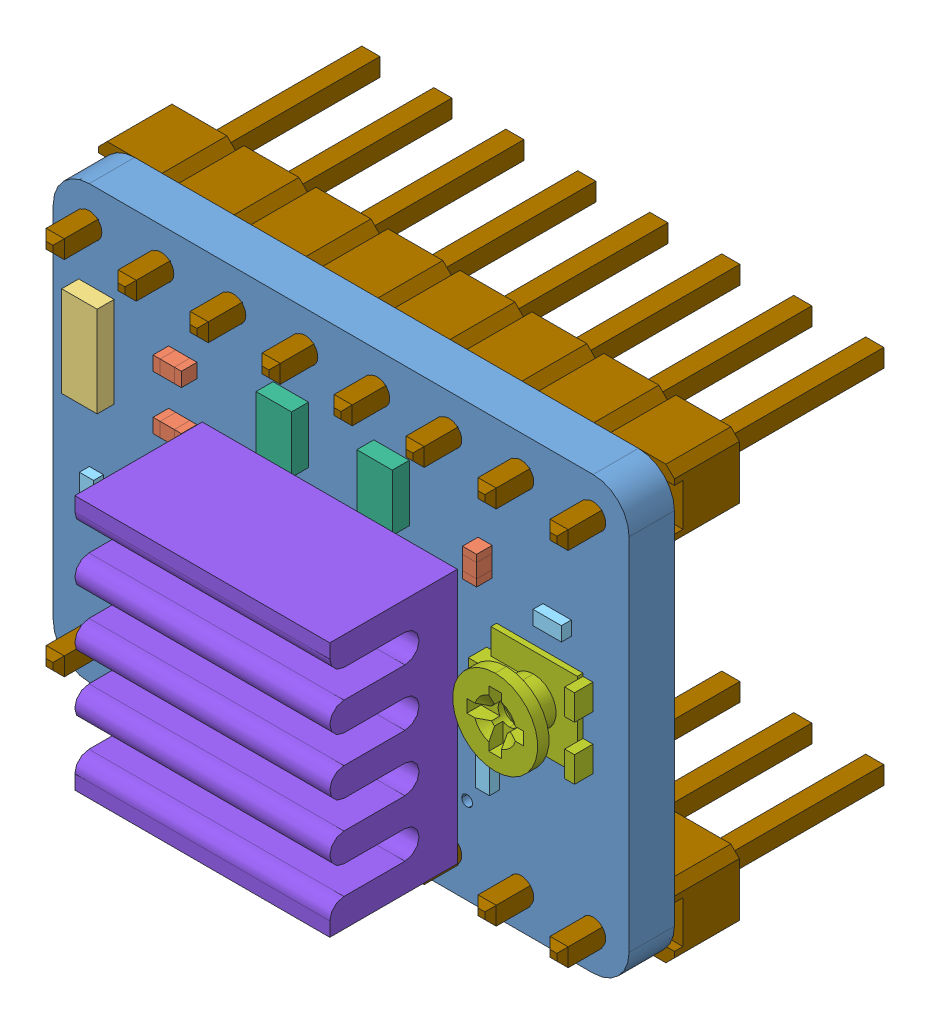
SolidWorks assembly A4988 RED, configuration Default. Lengths in mm.
Overall size (20.32 15.24 16.04).
20 component instances, 9 part files, 0 mates.
Components (placement in the parent):
- A4988 RED.STEP-1: A4988 RED.STEP [Default] at origin size (20.32 15.24 16.04)
  - stepstick.STEP-1: stepstick.STEP [Default] at origin size (20.32 15.24 1.6)
  - 0402CAP_CAP0402CAP.STEP-1: 0402CAP_CAP0402CAP.STEP [Default] at (55.372 62.23 1.6) x (-1 0 0) z (0 0 1) size (1 0.5 0.55)
  - 0402CAP_CAP0402CAP.STEP-2: 0402CAP_CAP0402CAP.STEP [Default] at (55.372 60.325 1.6) x (-1 0 0) z (0 0 1) size (1 0.5 0.55)
  - 0402CAP_CAP0402CAP.STEP-3: 0402CAP_CAP0402CAP.STEP [Default] at (66.04 61.595 1.6) x (0 -1 0) z (0 0 1) size (1 0.5 0.55)
  - 0402CAP_CAP0402CAP.STEP-4: 0402CAP_CAP0402CAP.STEP [Default] at (56.642 56.896 1.6) x (0 -1 0) z (0 0 1) size (1 0.5 0.55)
  - 0402CAP_CAP0402CAP.STEP-5: 0402CAP_CAP0402CAP.STEP [Default] at (54.483 55.626 1.6) size (1 0.5 0.55)
  - 0402CAP_CAP0402CAP.STEP-6: 0402CAP_CAP0402CAP.STEP [Default] at (57.023 54.356 1.6) size (1 0.5 0.55)
  - 1206_CAP1206.STEP-1: 1206_CAP1206.STEP [Default] at (52.324 61.341 1.6) x (0 1 0) z (0 0 1) size (3.2 1.25 0.6)
  - QFN28ET_A4983.STEP-1: QFN28ET_A4983.STEP [Default] at (60.96 57.15 1.6) size (5 5 0.9)
  - 0402RES_RESISTOR0402RES.STEP-1: 0402RES_RESISTOR0402RES.STEP [Default] at (68.58 60.96 1.6) size (1 0.5 0.35)
  - 0402RES_RESISTOR0402RES.STEP-2: 0402RES_RESISTOR0402RES.STEP [Default] at (52.324 56.896 1.6) x (0 -1 0) z (0 0 1) size (1 0.5 0.35)
  - 0402RES_RESISTOR0402RES.STEP-3: 0402RES_RESISTOR0402RES.STEP [Default] at (66.294 55.245 1.6) x (0 -1 0) z (0 0 1) size (1 0.5 0.35)
  - 0402RES_RESISTOR0402RES.STEP-4: 0402RES_RESISTOR0402RES.STEP [Default] at (64.008 53.848 1.6) size (1 0.5 0.35)
  - 0805_RESISTOR.STEP-1: 0805_RESISTOR.STEP [Default] at (59.182 62.23 1.6) x (0 -1 0) z (0 0 1) size (2 1.25 0.6)
  - 0805_RESISTOR.STEP-2: 0805_RESISTOR.STEP [Default] at (62.738 62.23 1.6) x (0 -1 0) z (0 0 1) size (2 1.25 0.6)
  - TRIMPOT3MM_TRIMPOTSMD.STEP-1: TRIMPOT3MM_TRIMPOTSMD.STEP [Default] at (67.945 58.293 1.6) x (0 1 0) z (0 0 1) size (3 3.75 1.55)
  - Heatsink For A4988.STEP-1: Heatsink For A4988.STEP [Default] at (61.96 57.65 2.5) x (0 1 0) z (1 0 0) size (9 5 9)
  - Pin header pitch 2.54mm_08 contacts.STEP-1: Pin header pitch 2.54mm_08 contacts.STEP [Default] at (69.85 52.045 -2.29) x (-1 0 0) z (0 0 -1) size (20.32 2.49 11.54)
  - Pin header pitch 2.54mm_08 contacts.STEP-2: Pin header pitch 2.54mm_08 contacts.STEP [Default] at (69.85 64.795 -2.29) x (-1 0 0) z (0 0 -1) size (20.32 2.49 11.54)
